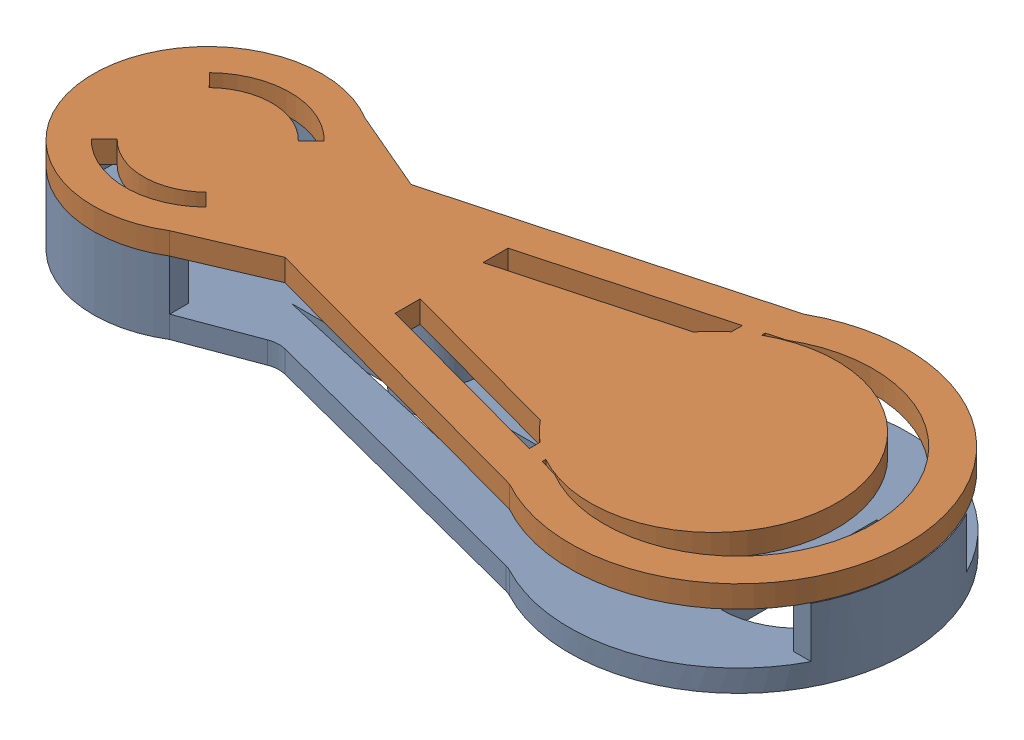
SolidWorks assembly final-toy, configuration Default. Lengths in mm.
Overall size (89 11.4 37).
2 component instances, 2 part files, 3 mates.
Components (placement in the parent):
- bottom-1: bottom [Default] at (9.5781 -6.1554 8.5188) size (89 7.9 37)
- top-1: top [Default] at (9.5781 1.7446 8.5188) size (88.9 11.4 36.8)
Mates (geometry in assembly coordinates):
- Coincident1: coincident anti-aligned: plane of bottom-1 through (9.5781 1.7446 8.5188) normal (0 1 0); plane of top-1 through (9.5781 1.7446 8.5188) normal (0 -1 0)
- Concentric2: concentric aligned: cylinder of bottom-1 through (-45.3043 -3.7554 8.5188) axis (0 -1 0) radius 12.5; cylinder of top-1 through (-45.3043 4.1446 8.5188) axis (0 -1 0) radius 12.5
- Concentric3: concentric aligned: cylinder of bottom-1 through (12.6957 -3.7554 8.5188) axis (0 -1 0) radius 18.5; cylinder of top-1 through (12.6957 4.1446 8.5188) axis (0 -1 0) radius 18.3977
